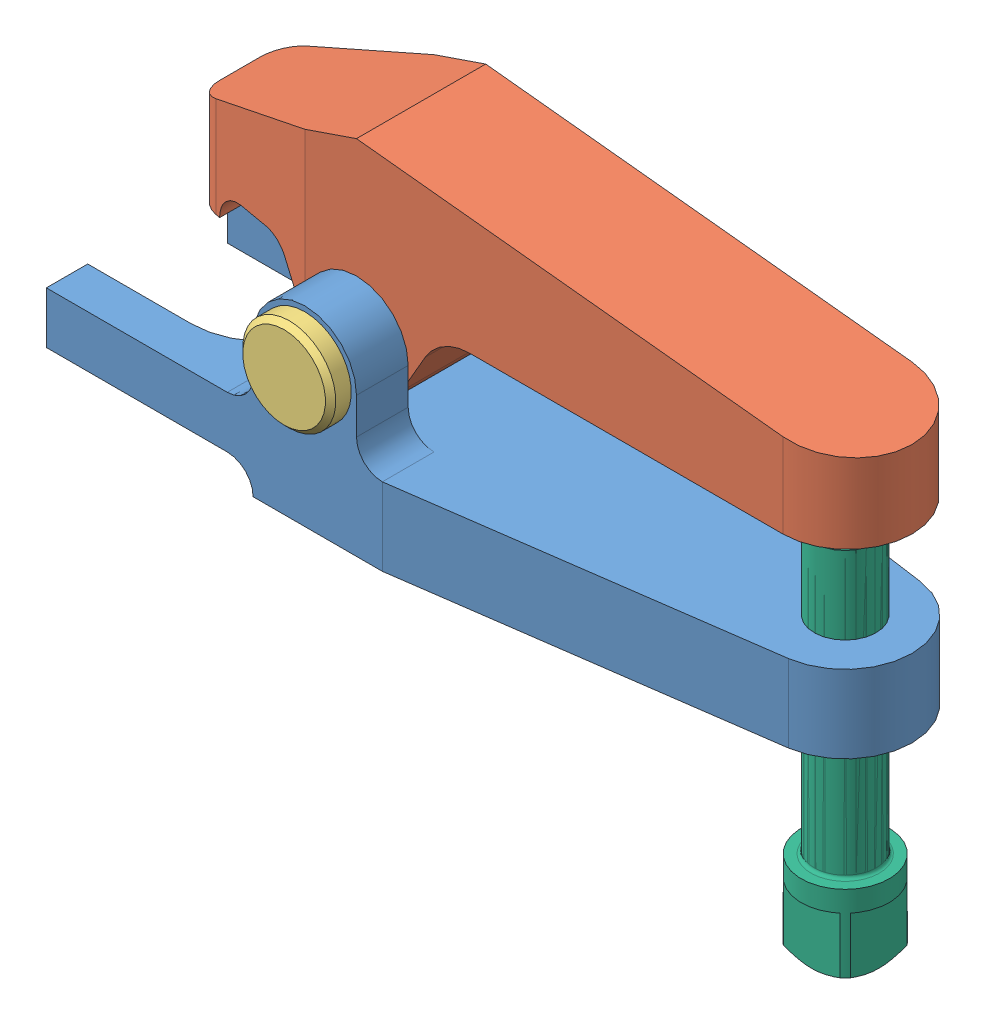
SolidWorks assembly Ściągacz sworzni, configuration Domyślna. Lengths in mm.
Overall size (145 101 59).
6 component instances, 6 part files, 13 mates.
Components (placement in the parent):
- Chwyt-1: Chwyt [Domyślna] at (4.0504 52.4852 113.2019) size (145 37 45)
- Ramię-1: Ramię [Domyślna] at (-0.9496 82.4852 100.7019) size (130 43 25)
- clevis pin headed_din-1: clevis pin headed_din [DIN EN 22341 - B - 10 x 55 x 3.2 - St] at (34.0504 79.4852 139.7019) x (0 0 -1) z (0 -1 0) size (59 18 18)
- plain washer clevis pin grade a_din-1: plain washer clevis pin grade a_din [DIN EN 28738 - 10] at (34.0504 79.4852 90.7019) x (0 0 1) z (-1 0 0) size (2.5 18 18)
- split pin_din-2: split pin_din [DIN 94-3.2x18-C-St] at (34.0504 84.4852 85.2019) x (0 -1 0) z (0 0 1) size (27.6 5.8 2.9)
- square head bolt oval pt_din-1: square head bolt oval pt_din [DIN 480 - M12 x 60-C] at (116.101 11.4852 113.2019) x (0 1 0) z (0.707107 0 0.707107) size (76 17 17)
Mates (geometry in assembly coordinates):
- Koncentryczne1: concentric aligned: cylinder of Chwyt-1 through (34.0504 79.4852 125.7019) axis (0 0 1) radius 5; cylinder of Ramię-1 through (34.0504 79.4852 100.7019) axis (0 0 1) radius 5
- Wspólnie1: coincident anti-aligned: plane of Chwyt-1 through (34.0504 79.4852 100.7019) normal (0 0 1); plane of Ramię-1 through (55.9897 77.4852 100.7019) normal (0 0 -1)
- Koncentryczne2: concentric anti-aligned: cylinder of Chwyt-1 through (34.0504 79.4852 100.7019) axis (0 0 -1) radius 5; cylinder of clevis pin headed_din-1 through (34.0504 79.4852 139.7019) axis (0 0 1) radius 5
- Wspólnie2: coincident anti-aligned: plane of Chwyt-1 through (-15.9496 67.4852 135.7019) normal (0 0 1); plane of clevis pin headed_din-1 through (43.0504 79.4852 135.7019) normal (0 0 -1)
- Koncentryczne3: concentric anti-aligned: cylinder of clevis pin headed_din-1 through (34.0504 79.4852 139.7019) axis (0 0 1) radius 5; cylinder of plain washer clevis pin grade a_din-1 through (34.0504 79.4852 55.7769) axis (0 0 -1) radius 5
- Wspólnie3: coincident anti-aligned: plane of Chwyt-1 through (49.0504 67.4852 90.7019) normal (0 0 -1); plane of plain washer clevis pin grade a_din-1 through (34.0504 84.4852 90.7019) normal (0 0 1)
- Koncentryczne4: concentric aligned: cylinder of clevis pin headed_din-1 through (34.0504 84.4852 85.2019) axis (0 -1 0) radius 1.6; cylinder of split pin_din-2 through (34.0504 84.4852 85.2019) axis (0 -1 0) radius 1.45
- Wspólnie4: coincident: cylinder of clevis pin headed_din-1 through (34.0504 79.4852 139.7019) axis (0 0 1) radius 5; point of split pin_din-2
- Koncentryczne5: concentric anti-aligned: cylinder of Chwyt-1 through (116.101 67.4852 113.2019) axis (0 1 0) radius 5.1; cylinder of square head bolt oval pt_din-1 through (116.101 11.4852 113.2019) axis (0 -1 0) radius 6
- Stycznie1: tangent anti-aligned: plane of Ramię-1 through (129.0504 87.4852 125.7019) normal (0 -1 0); sphere of square head bolt oval pt_din-1
- Równolegle1: parallel aligned: plane of Chwyt-1 through (49.0504 67.4852 90.7019) normal (0 0 -1); plane of square head bolt oval pt_din-1 through (110.6238 27.4852 106.7019) normal (0 0 -1)
- Równolegle2: parallel anti-aligned: plane of Chwyt-1 through (-15.9496 67.4852 90.7019) normal (-1 0 0); plane of split pin_din-2 through (34.0484 84.4852 86.6519) normal (1 0 0)
- Równolegle3: parallel anti-aligned: plane of Chwyt-1 through (116.101 67.4852 113.2019) normal (0 1 0); plane of Ramię-1 through (129.0504 87.4852 125.7019) normal (0 -1 0)
